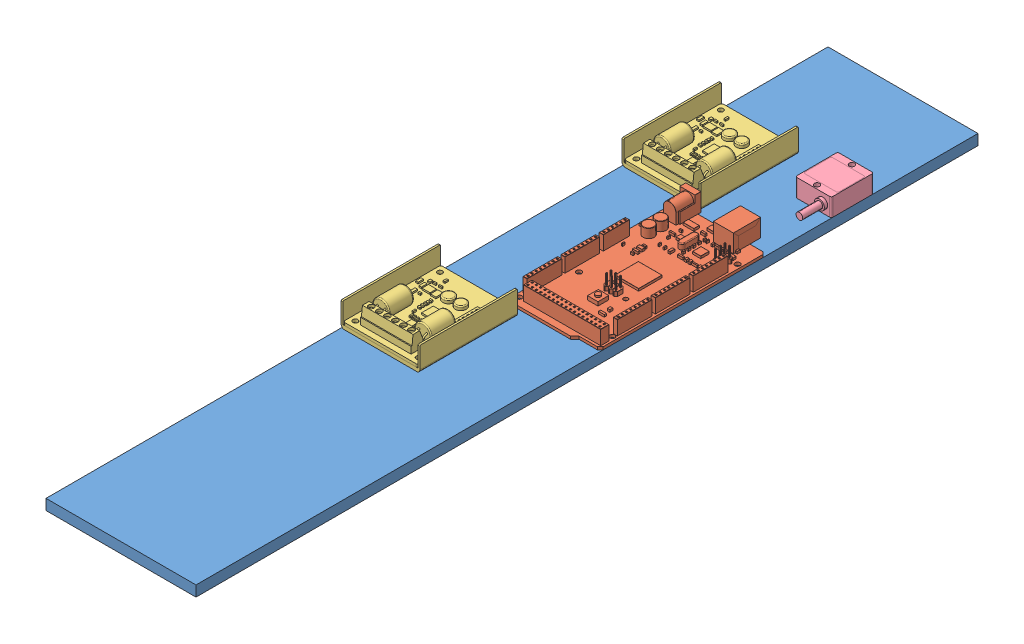
SolidWorks assembly electronics_plate2, configuration Default. Lengths in mm.
Overall size (90 20.96 469.2).
5 component instances, 4 part files, 12 mates.
Components (placement in the parent):
- electronics_plate-2: electronics_plate [Default] at (117.0343 251.6082 591.6759) size (90 6.35 469.2)
- ArduinoMega-2: ArduinoMega [Default] at (180.3262 259.6092 300.8759) x (0 0 -1) z (0 -1 0) size (107.95 53.42 12.95)
- motor_controller-1: motor_controller [Default] at (140.6563 260.1796 216.7494) x (0 0 -1) z (1 0 0) size (58.55 14.61 47.24)
- motor_controller-2: motor_controller [Default] at (140.6563 260.1796 385.2964) x (0 0 -1) z (1 0 0) size (58.55 14.61 47.24)
- Accelerometer-1: Accelerometer [Default] at (196.2343 263.3582 197.7882) x (0 0 -1) z (1 0 0) size (39.4 10.8 21.6)
Mates (geometry in assembly coordinates):
- Coincident1: coincident anti-aligned: plane of electronics_plate-2 through (117.0343 257.9582 591.6759) normal (0 1 0); plane of ArduinoMega-2 through (153.6181 257.9582 250.0759) normal (0 -1 0)
- Coincident6: coincident anti-aligned: line of electronics_plate-2 through (207.0343 257.9582 591.6759) axis (0 0 -1); line of ArduinoMega-2 through (207.0343 257.9582 251.5999) axis (0 0 1)
- Distance8: distance = 240 mm: line of ArduinoMega-2 through (191.7943 257.9582 351.6759) axis (-1 0 0); line of electronics_plate-2 through (117.0343 257.9582 591.6759) axis (1 0 0)
- Coincident15: coincident anti-aligned: plane of electronics_plate-2 through (117.0343 257.9582 591.6759) normal (0 1 0); plane of motor_controller-1 through (164.2783 257.9582 143.0259) normal (0 -1 0)
- Distance7: distance = 65 mm: line of electronics_plate-2 through (207.0343 257.9582 122.4759) axis (-1 0 0); line of motor_controller-1 through (162.3733 257.9582 187.4759) axis (-1 0 0)
- Coincident17: coincident aligned: plane of electronics_plate-2 through (117.0343 257.9582 591.6759) normal (-1 0 0); plane of motor_controller-1 through (117.0343 272.5632 143.0259) normal (-1 0 0)
- Coincident18: coincident anti-aligned: plane of electronics_plate-2 through (117.0343 257.9582 591.6759) normal (0 1 0); plane of motor_controller-2 through (164.2783 257.9582 311.5729) normal (0 -1 0)
- Distance5: distance = 0 mm aligned: plane of electronics_plate-2 through (117.0343 257.9582 591.6759) normal (-1 0 0); plane of motor_controller-2 through (117.0343 272.5632 306.5729) normal (-1 0 0)
- Distance6: distance = 110 mm anti-aligned: plane of motor_controller-2 through (163.1353 261.8306 356.0229) normal (0 0 -1); plane of motor_controller-1 through (140.6563 260.1796 246.0229) normal (0 0 1)
- Distance10: distance = 0 mm: line of electronics_plate-2 through (207.0343 257.9582 591.6759) axis (0 0 -1); line of Accelerometer-1 through (207.0343 257.9582 209.4882) axis (0 0 -1)
- Coincident26: coincident anti-aligned: plane of electronics_plate-2 through (117.0343 257.9582 591.6759) normal (0 1 0); plane of Accelerometer-1 through (196.2343 257.9582 197.7882) normal (0 -1 0)
- Distance12: distance = 381.1876 mm: line of Accelerometer-1 through (186.4343 257.9582 210.4882) axis (1 0 0); line of electronics_plate-2 through (117.0343 257.9582 591.6759) axis (1 0 0)
